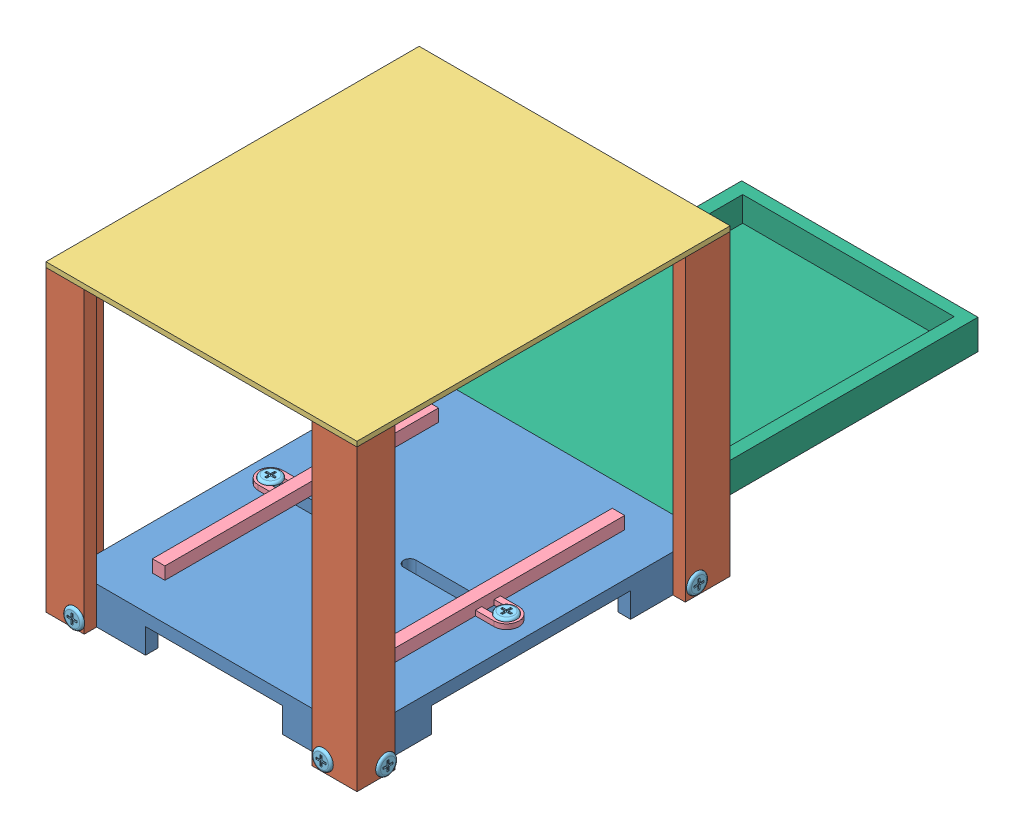
SolidWorks assembly Scantron Machine, configuration Default. Lengths in mm.
Overall size (322.58 310.28 675.64).
19 component instances, 6 part files, 32 mates.
Components (placement in the parent):
- Scantron Machine Base Plate-1: Scantron Machine Base Plate [Default] at origin size (292.1 38.1 355.6)
- Leg for Scantron Machine-1: Leg for Scantron Machine [Default] at (-82.6065 -25.4 -107.384) size (45.8 304.8 39.03)
- Leg for Scantron Machine-2: Leg for Scantron Machine [Default] at (82.6065 -25.4 107.384) x (-1 0 0) z (0 0 -1) size (45.8 304.8 39.03)
- Leg for Scantron Machine-3: Leg for Scantron Machine [Default] at (75.634 -25.4 -114.3565) x (0 0 1) z (-1 0 0) size (45.8 304.8 39.03)
- Leg for Scantron Machine-4: Leg for Scantron Machine [Default] at (-75.634 -25.4 114.3565) x (0 0 -1) z (1 0 0) size (45.8 304.8 39.03)
- Top Plate-1: Top Plate [Default] at (0 279.4 0) size (317.5 5.08 381)
- slider-1: slider [Default] at (-94.4838 12.7 0) size (44.45 12.7 279.4)
- slider-2: slider [Default] at (95.5625 12.7 0) x (-1 0 0) z (0 0 -1) size (44.45 12.7 279.4)
- screw-1: screw [Default] at (-133.35 -15.6417 -161.2251) x (0 1 0) z (0 0 1) size (20.32 27.94 20.32)
- screw-2: screw [Default] at (-129.4751 -15.6417 165.1) x (1 0 0) z (0 -1 0) size (20.32 27.94 20.32)
- screw-3: screw [Default] at (133.35 -15.6417 161.2251) x (0 -1 0) z (0 0 1) size (20.32 27.94 20.32)
- screw-4: screw [Default] at (120.9625 -7.62 0) size (20.32 27.94 20.32)
- screw-5: screw [Default] at (-133.35 -13.9498 156.1493) x (0 1 0) z (0 0 1) size (20.32 27.94 20.32)
- screw-6: screw [Default] at (124.3993 -13.9498 165.1) x (1 0 0) z (0 -1 0) size (20.32 27.94 20.32)
- screw-7: screw [Default] at (133.35 -13.9498 -156.1493) x (0 -1 0) z (0 0 1) size (20.32 27.94 20.32)
- screw-8: screw [Default] at (129.4751 -15.6417 -165.1) x (1 0 0) z (0 1 0) size (20.32 27.94 20.32)
- screw-9: screw [Default] at (-124.3993 -13.9498 -165.1) x (1 0 0) z (0 1 0) size (20.32 27.94 20.32)
- screw-10: screw [Default] at (-119.8838 -7.62 0) size (20.32 27.94 20.32)
- scantron tray-1: scantron tray [Default] at (-0.9333 7.62 -330.2) x (-1 0 0) z (0 0 -1) size (241.3 30.48 304.8)
Mates (geometry in assembly coordinates):
- Coincident1: coincident aligned: line of Scantron Machine Base Plate-1 through (-146.05 12.7 177.8) axis (0 -1 0); line of Leg for Scantron Machine-4 through (-146.05 279.4 177.8) axis (0 -1 0)
- Coincident2: coincident anti-aligned: plane of Scantron Machine Base Plate-1 through (0 12.7 177.8) normal (0 0 1); plane of Leg for Scantron Machine-4 through (-75.634 279.4 177.8) normal (0 0 -1)
- Coincident3: coincident aligned: plane of Scantron Machine Base Plate-1 through (0 -25.4 0) normal (0 -1 0); plane of Leg for Scantron Machine-4 through (-75.634 -25.4 114.3565) normal (0 -1 0)
- Coincident4: coincident aligned: line of Scantron Machine Base Plate-1 through (146.05 12.7 177.8) axis (0 -1 0); line of Leg for Scantron Machine-2 through (146.05 279.4 177.8) axis (0 -1 0)
- Coincident5: coincident anti-aligned: plane of Scantron Machine Base Plate-1 through (0 12.7 177.8) normal (0 0 1); plane of Leg for Scantron Machine-2 through (82.6065 279.4 177.8) normal (0 0 -1)
- Coincident6: coincident aligned: plane of Scantron Machine Base Plate-1 through (0 -25.4 0) normal (0 -1 0); plane of Leg for Scantron Machine-2 through (82.6065 -25.4 107.384) normal (0 -1 0)
- Coincident7: coincident aligned: line of Scantron Machine Base Plate-1 through (-146.05 12.7 -177.8) axis (0 -1 0); line of Leg for Scantron Machine-1 through (-146.05 279.4 -177.8) axis (0 -1 0)
- Coincident8: coincident anti-aligned: plane of Scantron Machine Base Plate-1 through (0 12.7 -177.8) normal (0 0 -1); plane of Leg for Scantron Machine-1 through (-82.6065 279.4 -177.8) normal (0 0 1)
- Coincident9: coincident aligned: plane of Scantron Machine Base Plate-1 through (0 -25.4 0) normal (0 -1 0); plane of Leg for Scantron Machine-1 through (-82.6065 -25.4 -107.384) normal (0 -1 0)
- Coincident10: coincident aligned: line of Scantron Machine Base Plate-1 through (146.05 12.7 -177.8) axis (0 -1 0); line of Leg for Scantron Machine-3 through (146.05 279.4 -177.8) axis (0 -1 0)
- Coincident11: coincident anti-aligned: plane of Scantron Machine Base Plate-1 through (146.05 12.7 0) normal (1 0 0); plane of Leg for Scantron Machine-3 through (146.05 279.4 -114.3565) normal (-1 0 0)
- Coincident12: coincident aligned: plane of Scantron Machine Base Plate-1 through (0 -25.4 0) normal (0 -1 0); plane of Leg for Scantron Machine-3 through (75.634 -25.4 -114.3565) normal (0 -1 0)
- Coincident13: coincident: point of Leg for Scantron Machine-2; point of Top Plate-1
- Coincident14: coincident aligned: plane of Scantron Machine Base Plate-1 through (-123.825 0 -6.35) normal (0 0 1); plane of slider-1 through (-94.4838 17.78 -6.35) normal (0 0 1)
- Parallel1: parallel aligned: plane of Scantron Machine Base Plate-1 through (-123.825 0 -6.35) normal (0 0 1); plane of slider-1 through (-94.4838 17.78 -6.35) normal (0 0 1)
- Coincident17: coincident anti-aligned: plane of Scantron Machine Base Plate-1 through (0 12.7 0) normal (0 1 0); plane of slider-1 through (-94.4838 12.7 0) normal (0 -1 0)
- Coincident18: coincident aligned: plane of Scantron Machine Base Plate-1 through (123.825 0 6.35) normal (0 0 -1); plane of slider-2 through (95.5625 17.78 6.35) normal (0 0 -1)
- Coincident21: coincident aligned: plane of Scantron Machine Base Plate-1 through (123.825 0 6.35) normal (0 0 -1); plane of slider-2 through (95.5625 17.78 6.35) normal (0 0 -1)
- Coincident22: coincident anti-aligned: plane of Scantron Machine Base Plate-1 through (0 12.7 0) normal (0 1 0); plane of slider-2 through (95.5625 12.7 0) normal (0 -1 0)
- Coincident23: coincident aligned: circle of Leg for Scantron Machine-2; circle of screw-3
- Coincident24: coincident aligned: circle of Leg for Scantron Machine-2; circle of screw-6
- Coincident25: coincident aligned: circle of Leg for Scantron Machine-4; circle of screw-2
- Coincident26: coincident aligned: circle of Leg for Scantron Machine-3; circle of screw-7
- Coincident27: coincident aligned: circle of Leg for Scantron Machine-3; circle of screw-8
- Coincident28: coincident aligned: circle of Leg for Scantron Machine-4; circle of screw-5
- Coincident30: coincident aligned: circle of Leg for Scantron Machine-1; circle of screw-1
- Coincident31: coincident aligned: circle of Leg for Scantron Machine-1; circle of screw-9
- Coincident32: coincident aligned: circle of slider-1; circle of screw-10
- Coincident33: coincident aligned: circle of slider-2; circle of screw-4
- Coincident34: coincident anti-aligned: line of Scantron Machine Base Plate-1 through (-146.05 12.7 -177.8) axis (1 0 0); line of scantron tray-1 through (119.7167 12.7 -177.8) axis (-1 0 0)
- Coincident35: coincident anti-aligned: plane of Scantron Machine Base Plate-1 through (0 12.7 -177.8) normal (0 0 -1); plane of scantron tray-1 through (-0.9333 12.7 -177.8) normal (0 0 1)
- Coincident36: coincident anti-aligned: plane of Leg for Scantron Machine-3 through (119.7167 279.4 -114.3565) normal (-1 0 0); plane of scantron tray-1 through (119.7167 12.7 -330.2) normal (1 0 0)
